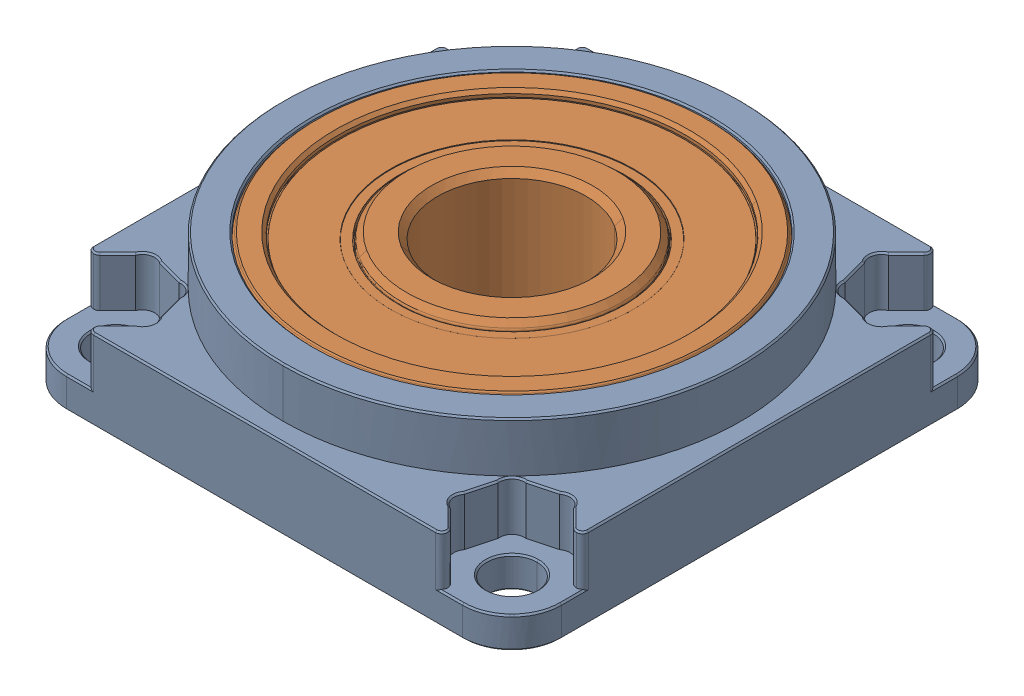
SolidWorks assembly 1622-0032-0012 assembly(2), configuration Default. Lengths in mm.
Overall size (44.21 10.5 44.21).
2 component instances, 2 part files, 0 mates.
Components (placement in the parent):
- 1622-0032-0012_1-1: 1622-0032-0012_1 [Default] at (-26.5906 -3.5812 12.8977) size (40 10.5 40)
- 1600-1032-0012_1-1: 1600-1032-0012_1 [Default] at (-26.5906 1.9188 12.8977) x (0.842116 0 0.539296) z (-0.539296 0 0.842116) size (32 10 32)
